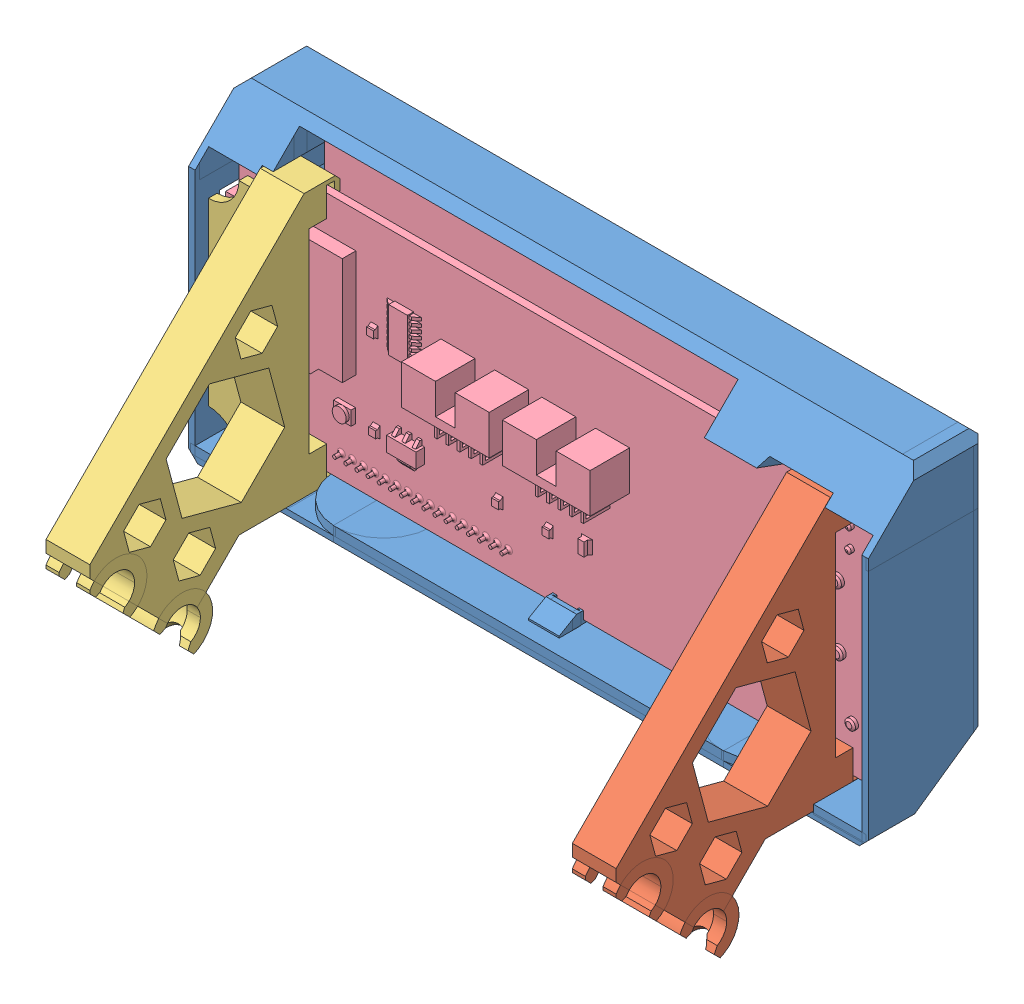
SolidWorks assembly Assembly lcd, configuration Valor predeterminado. Lengths in mm.
Overall size (155 93.68 88.88).
4 component instances, 4 part files, 13 mates.
Components (placement in the parent):
- LCD-cover-1: LCD-cover [Valor predeterminado] at (-0.5 14 0) size (155 70 26)
- LCD-support-A-1: LCD-support-A [Valor predeterminado] at (65 61.65 21) x (0 0.707107 -0.707107) z (-1 0 0) size (78.2 47.49 10.1)
- LCD-support-B-1: LCD-support-B [Valor predeterminado] at (-55 61.65 21) x (0 0.707107 -0.707107) z (-1 0 0) size (78.2 47.49 20.05)
- LCD Smart controller 2004-1: LCD Smart controller 2004 [Valor predeterminado] at (0 31.65 15.25) x (1 0 0) z (0 0 -1) size (150 63 24.8)
Mates (geometry in assembly coordinates):
- Simétrico1: symmetric: plane of assembly; plane of assembly; plane of LCD-cover-1 through (-77.5 -0.7 0) normal (-1 0 0); plane of LCD-cover-1 through (77.5 -0.7 0) normal (1 0 0); plane of assembly
- Simétrico2: symmetric: plane of assembly; plane of assembly; plane of LCD-cover-1 through (-77.5 -0.7 0) normal (-1 0 0); plane of LCD-cover-1 through (77.5 -0.7 0) normal (1 0 0); plane of assembly
- Coincidente7: coincident: plane of assembly through (0 0 0) normal (0 0 1); plane of LCD-cover-1 through (-77.5 9.5 0) normal (0 0 -1); plane of assembly
- Coincidente8: coincident: plane of assembly through (0 0 0) normal (0 1 0); plane of LCD-cover-1 through (-100.5 0 0) normal (0 -1 0); plane of assembly
- Coincidente9: coincident: plane of assembly; plane of assembly; plane of LCD-cover-1 through (-60 14 0) normal (1 0 0); plane of LCD-support-B-1 through (-60 61.65 21) normal (1 0 0)
- Coincidente10: coincident: plane of assembly; plane of assembly; plane of LCD-cover-1 through (-0.5 31.65 0) normal (0 1 0); plane of LCD-support-B-1 through (-55 31.65 21) normal (0 1 0)
- Coincidente11: coincident: plane of assembly; plane of assembly; plane of LCD-cover-1 through (60 14 0) normal (1 0 0); plane of LCD-support-A-1 through (60 61.65 21) normal (-1 0 0)
- Coincidente12: coincident: plane of assembly; plane of assembly; plane of LCD-cover-1 through (-0.5 31.65 0) normal (0 1 0); plane of LCD-support-A-1 through (65 31.65 21) normal (0 -1 0)
- Coincidente13: coincident: plane of assembly; plane of assembly; plane of LCD-cover-1 through (-65 1.3 14) normal (0 0 1); plane of LCD-support-B-1 through (-54 64.65 14) normal (0 0 -1)
- Coincidente14: coincident: plane of assembly; plane of assembly; plane of LCD-cover-1 through (55 1.3 14) normal (0 0 1); plane of LCD-support-A-1 through (66 64.65 14) normal (0 0 -1)
- Coincidente15: coincident: plane of assembly through (0 0 0) normal (1 0 0); plane of LCD Smart controller 2004-1 through (0 31.65 15.25) normal (1 0 0); plane of assembly
- Coincidente16: coincident: plane of assembly through (0 0 16.1) normal (0 0 1); plane of LCD Smart controller 2004-1 through (0 31.65 16.1) normal (0 0 -1); plane of assembly
- Coincidente17: coincident: plane of assembly; plane of assembly; plane of LCD-support-A-1 through (65 31.65 21) normal (0 -1 0); plane of LCD Smart controller 2004-1 through (0 31.65 15.25) normal (0 -1 0)
